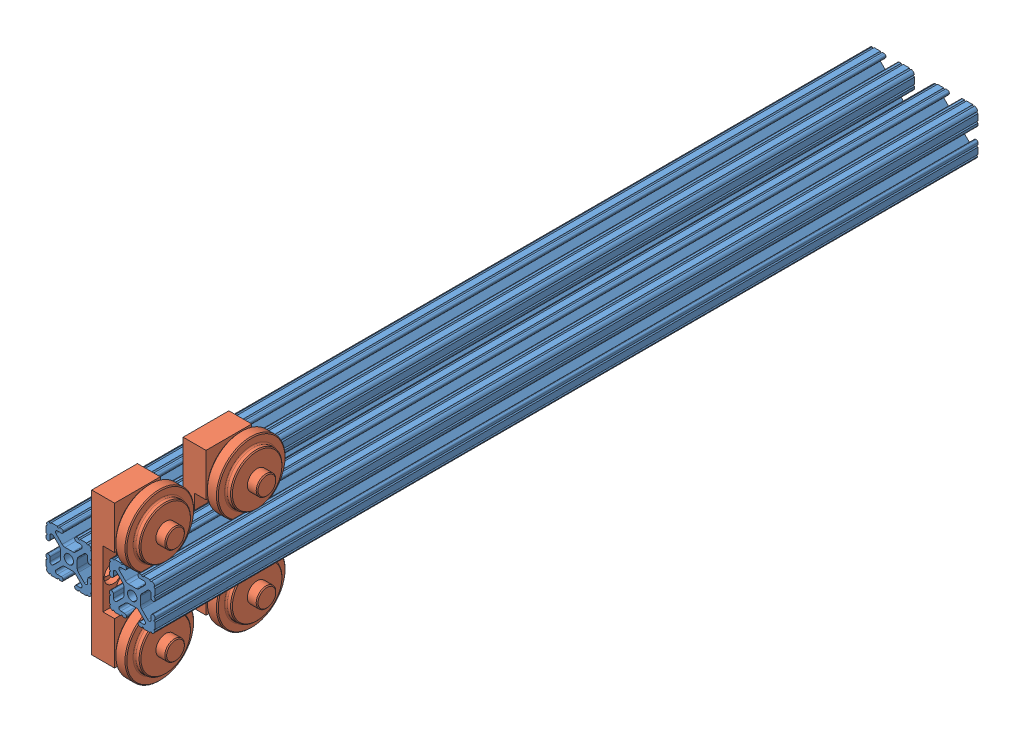
SolidWorks assembly 80 20, configuration Default. Lengths in mm.
Overall size (60.6 92.08 463.55).
4 component instances, 2 part files, 10 mates.
Components (placement in the parent):
- 47065T554_T-Slotted Framing-1: 47065T554_T-Slotted Framing [47065T554] at (184.1981 252.7447 334.1814) size (25.4 25.4 457.2)
- 47065T554_T-Slotted Framing-2: 47065T554_T-Slotted Framing [47065T554] at (219.4025 252.7193 334.1814) size (25.4 25.4 457.2)
- 47065T973_T-Slotted Framing wheeld-1: 47065T973_T-Slotted Framing wheeld [47065T973] at (219.1993 252.7447 550.0814) size (33.83 92.08 38.1)
- 47065T973_T-Slotted Framing wheeld-2: 47065T973_T-Slotted Framing wheeld [47065T973] at (219.1993 252.7447 499.2814) size (33.83 92.08 38.1)
Mates (geometry in assembly coordinates):
- Coincident1: coincident anti-aligned: plane of 47065T554_T-Slotted Framing-1 through (196.8981 256.9351 562.7814) normal (1 0 0); plane of 47065T973_T-Slotted Framing wheeld-1 through (196.8981 292.4322 562.7814) normal (-1 0 0)
- Coincident2: coincident aligned: plane of 47065T554_T-Slotted Framing-1 through (188.3884 240.9839 562.7814) normal (0 0 1); plane of 47065T973_T-Slotted Framing wheeld-1 through (196.8981 292.4322 562.7814) normal (0 0 1)
- Distance1: distance = 26.9875 mm aligned: plane of 47065T554_T-Slotted Framing-1 through (188.3884 265.4447 562.7814) normal (0 1 0); plane of 47065T973_T-Slotted Framing wheeld-1 through (209.5981 292.4322 562.7814) normal (0 1 0)
- Coincident4: coincident anti-aligned: plane of 47065T554_T-Slotted Framing-2 through (216.1513 241.2899 562.7814) normal (1 0 0); plane of 47065T973_T-Slotted Framing wheeld-1 through (216.1513 244.2992 550.0814) normal (-1 0 0)
- Tangent1: tangent anti-aligned: plane of 47065T554_T-Slotted Framing-2 through (215.2121 240.0193 562.7814) normal (0 -1 0); cylinder of 47065T973_T-Slotted Framing wheeld-1 through (201.5209 225.7572 550.0814) axis (-1 0 0) radius 14.2621
- Parallel2: parallel aligned: plane of 47065T554_T-Slotted Framing-1 through (188.3884 240.9839 562.7814) normal (0 0 1); plane of 47065T554_T-Slotted Framing-2 through (223.5928 240.9585 562.7814) normal (0 0 1)
- LimitDistance1: limit distance = 0 mm aligned: plane of 47065T554_T-Slotted Framing-2 through (223.5928 240.9585 105.5814) normal (0 0 -1); plane of 47065T554_T-Slotted Framing-1 through (188.3884 240.9839 105.5814) normal (0 0 -1)
- Coincident8: coincident anti-aligned: plane of 47065T554_T-Slotted Framing-1 through (196.8981 256.9351 562.7814) normal (1 0 0); plane of 47065T973_T-Slotted Framing wheeld-2 through (196.8981 292.4322 511.9814) normal (-1 0 0)
- Distance4: distance = 26.9875 mm aligned: plane of 47065T973_T-Slotted Framing wheeld-2 through (209.5981 292.4322 511.9814) normal (0 1 0); plane of 47065T554_T-Slotted Framing-1 through (188.3884 265.4447 562.7814) normal (0 1 0)
- Distance5: distance = 25.4 mm: plane of 47065T973_T-Slotted Framing wheeld-2 through (196.8981 292.4322 511.9814) normal (0 0 1); line of 47065T973_T-Slotted Framing wheeld-1 through (209.5981 292.4322 537.3814) axis (-1 0 0)
